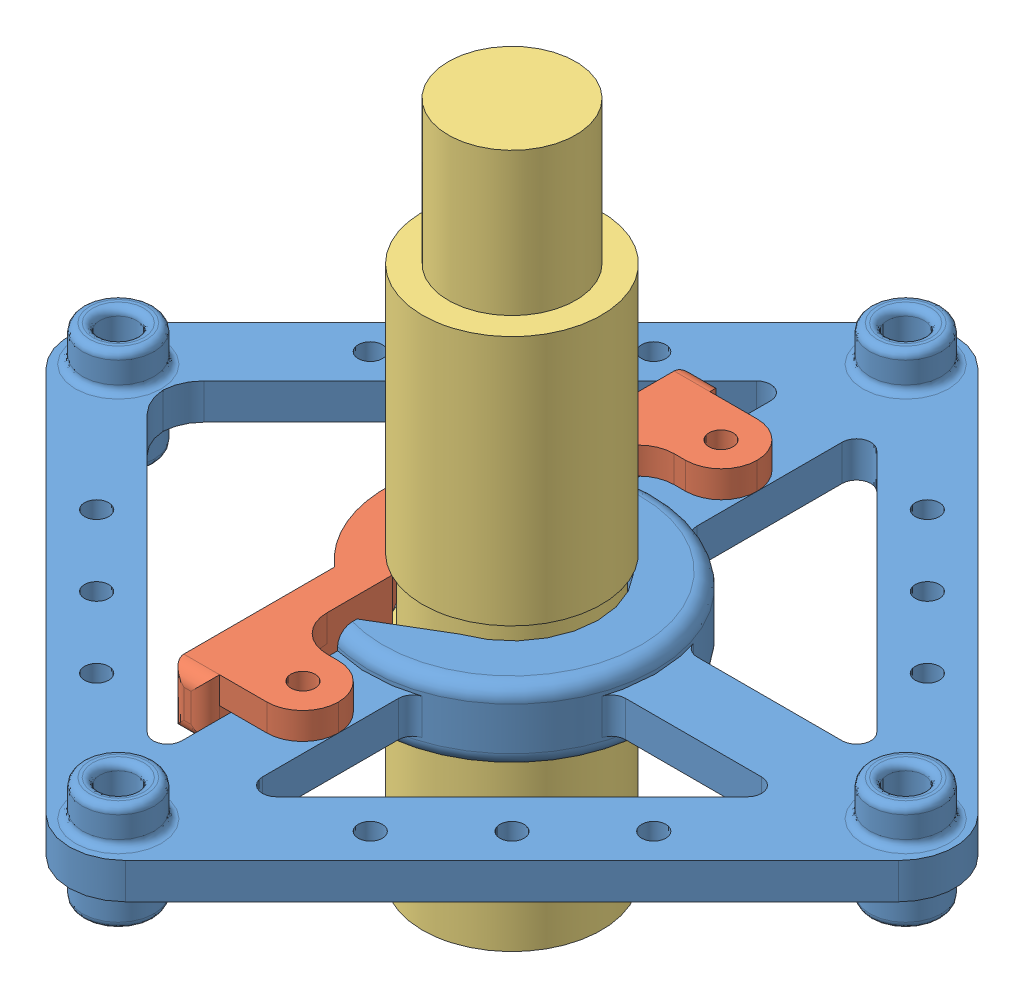
SolidWorks assembly TEST Reg Restraint structure, configuration Default. Lengths in mm.
Overall size (161.21 119.89 161.21).
3 component instances, 3 part files, 6 mates.
Components (placement in the parent):
- N-C PLA Reg Cradle V2-1: N-C PLA Reg Cradle V2 [Default] at (58.6672 100.3459 120.2177) size (161.21 19.05 161.21)
- N-C PLA Reg Restraint V2-1: N-C PLA Reg Restraint V2 [Default] at (58.5402 103.2034 120.2177) x (-1 0 0) z (0 0 -1) size (28.7 10.16 92.07)
- LoFi Reg 2-1: LoFi Reg 2 [Default] at (58.6672 59.4046 120.2177) x (0.976896 0 -0.213713) z (0.213713 0 0.976896) size (31.75 119.89 31.75)
Mates (geometry in assembly coordinates):
- Concentric1: concentric aligned: circle of N-C PLA Reg Cradle V2-1; circle of LoFi Reg 2-1
- Parallel1: parallel aligned: line of N-C PLA Reg Cradle V2-1 through (52.3172 103.5209 144.8112) axis (0 0 1); line of N-C PLA Reg Restraint V2-1 through (43.9352 108.2834 136.9091) axis (0 0 1)
- Coincident2: coincident anti-aligned: plane of N-C PLA Reg Cradle V2-1 through (52.3172 103.5209 193.8086) normal (-1 0 0); plane of N-C PLA Reg Restraint V2-1 through (50.2852 103.2034 77.9177) normal (1 0 0)
- Coincident8: coincident aligned: circle of N-C PLA Reg Cradle V2-1; circle of N-C PLA Reg Restraint V2-1
- Coincident10: coincident aligned: circle of N-C PLA Reg Restraint V2-1; circle of N-C PLA Reg Cradle V2-1
- Parallel3: parallel anti-aligned: line of N-C PLA Reg Cradle V2-1 through (52.3172 103.5209 67.9832) axis (0 0 1); line of N-C PLA Reg Restraint V2-1 through (43.9352 108.2834 103.4653) axis (0 0 -1)
